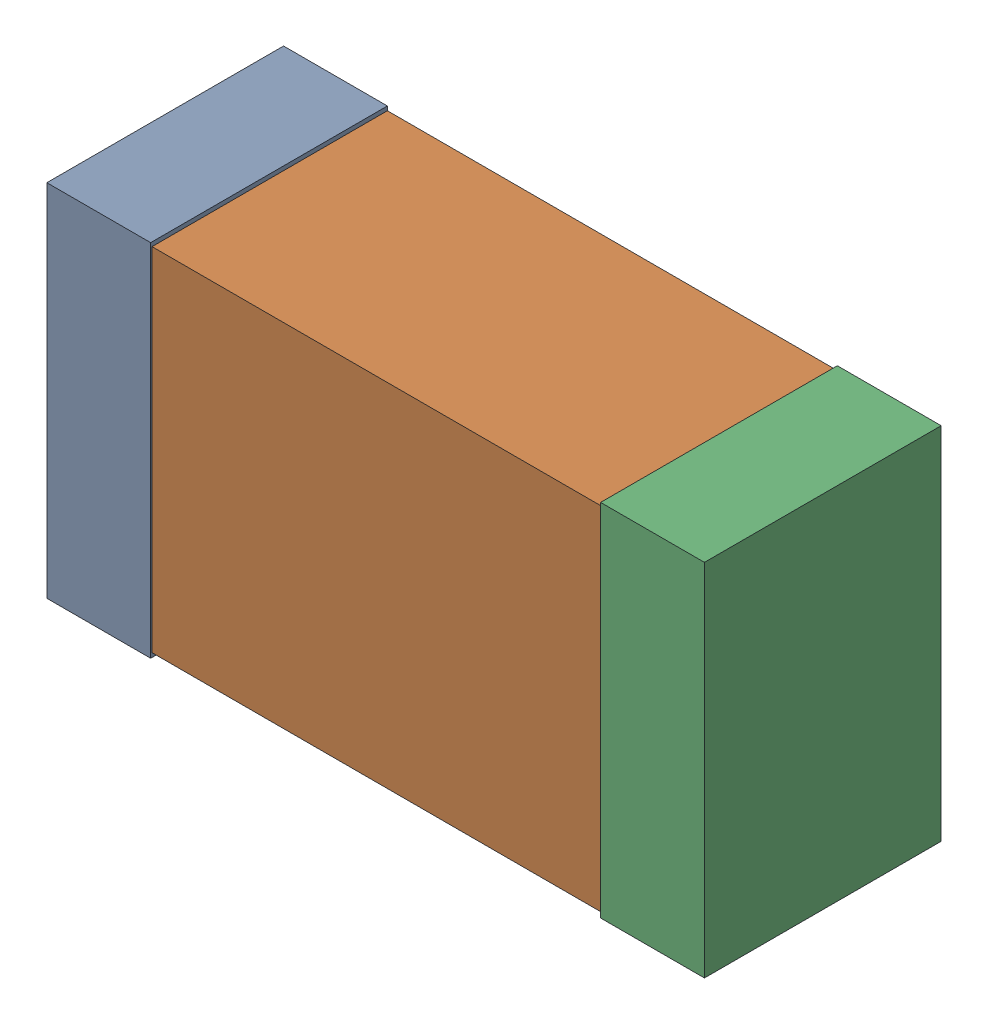
SolidWorks assembly R2Kanaloa_v2.0.0_GPIO_b, configuration Default. Lengths in mm.
Overall size (2.38 1.3 0.85).
6 component instances, 2 part files, 0 mates.
Components (placement in the parent):
- 352877648-1: 352877648 [Default] at (38.497 136.398 0) size (0.38 1.3 0.85)
  - Extruded_14-1: Extruded_14 [Default] at origin size (0.38 1.3 0.85)
- 352877392-1: 352877392 [Default] at (39.497 136.398 0) size (2.2 1.27 0.85)
  - Extruded_15-1: Extruded_15 [Default] at origin size (2.2 1.27 0.85)
- 352877648-2: 352877648 [Default] at (40.497 136.398 0) size (0.38 1.3 0.85)
  - Extruded_14-1: Extruded_14 [Default] at origin size (0.38 1.3 0.85)
